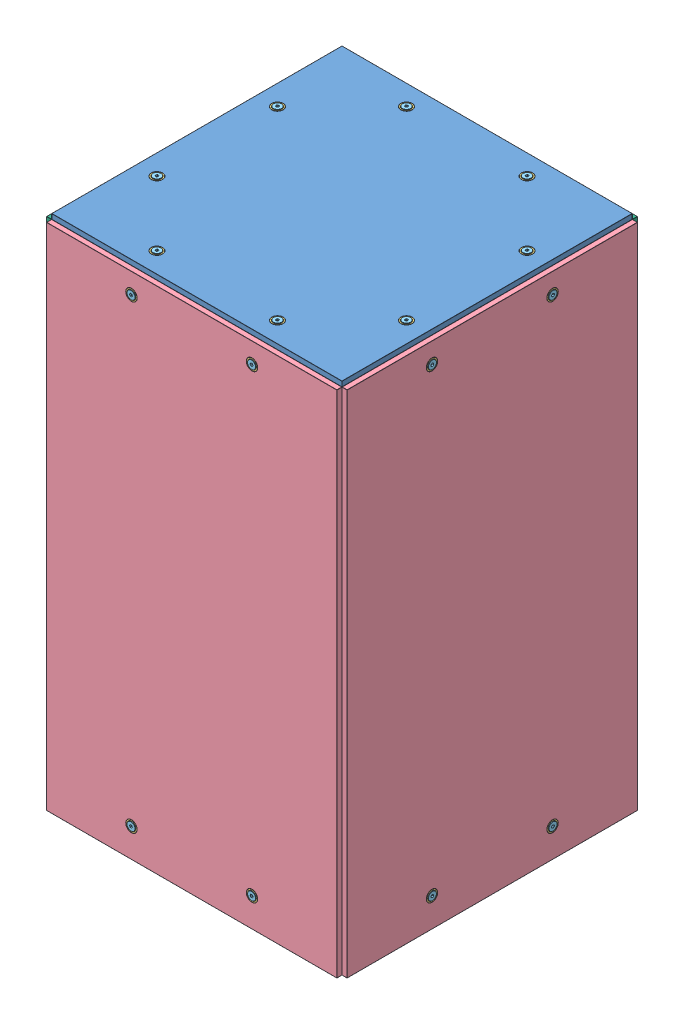
SolidWorks assembly SC.1.GD-PH, configuration Glass Dome 354 x 354 x 600. Lengths in mm.
Overall size (355.03 606.51 355.03).
85 component instances, 7 part files, 48 mates.
Components (placement in the parent):
- SC.1.G.PH.T-1: SC.1.G.PH.T [Topo 342 x 342] at (-2.0067 135.176 -92.8158)
- SC.1.L-1: SC.1.L [Default] at (-79.5067 117.926 60.9342) x (0 0 -1) z (1 0 0)
- SC.1.AC2-1: SC.1.AC2 [Default] at (-73.0067 136.176 54.1842) x (0 -1 0) z (0 0 1)
- SC.1.L-2: SC.1.L [Default] at (151.7433 117.926 -15.3158) x (-1 0 0) z (0 0 -1)
- SC.1.AC2-2: SC.1.AC2 [Default] at (144.9933 136.176 -21.8158) x (0 -1 0) z (0 0 1)
- SC.1.AC2-3: SC.1.AC2 [Default] at (68.9933 136.176 54.1842) x (0 -1 0) z (0 0 -1)
- SC.1.L-3: SC.1.L [Default] at (62.4933 117.926 60.9342) x (0 0 -1) z (1 0 0)
- SC.1.AC2-4: SC.1.AC2 [Default] at (144.9933 136.176 -163.8158) x (0 -1 0) z (0 0 1)
- SC.1.L-4: SC.1.L [Default] at (151.7433 117.926 -157.3158) x (-1 0 0) z (0 0 -1)
- SC.1.AC2-5: SC.1.AC2 [Default] at (-149.0067 136.176 -21.8158) x (0 -1 0) z (0 0 -1)
- SC.1.L-5: SC.1.L [Default] at (-155.7567 117.926 -28.3158)
- SC.1.AC2-6: SC.1.AC2 [Default] at (-149.0067 136.176 -163.8158) x (0 -1 0) z (0 0 -1)
- SC.1.L-6: SC.1.L [Default] at (-155.7567 117.926 -170.3158)
- SC.1.AC2-7: SC.1.AC2 [Default] at (68.9933 136.176 -239.8158) x (0 -1 0) z (0 0 -1)
- SC.1.L-7: SC.1.L [Default] at (75.4933 117.926 -246.5658) x (0 0 1) z (-1 0 0)
- SC.1.AC2-8: SC.1.AC2 [Default] at (-73.0067 136.176 -239.8158) x (0 -1 0) z (0 0 1)
- SC.1.L-8: SC.1.L [Default] at (-66.5067 117.926 -246.5658) x (0 0 1) z (-1 0 0)
- SC.1.G.PH.L-1: SC.1.G.PH.L [Lateral 342 x 600] at (-2.0067 -164.824 78.1842)
- SC.1.G.PH.L-5: SC.1.G.PH.L [Lateral 342 x 600] at (168.9933 -164.824 -92.8158) x (0 0 -1) z (1 0 0)
- SC.1.AC2-10: SC.1.AC2 [Default] at (-73.0067 111.176 79.1842) x (0 0 -1) z (0 -1 0)
- SC.1.AC2-11: SC.1.AC2 [Default] at (169.9933 111.176 -21.8158) x (-1 0 0) z (0 0 1)
- SC.1.P7991-12-1: SC.1.P7991-12 [ISO 10642 - M5 x 12 --- 12N] at (-73.0067 141.6902 54.1842) x (0 -1 0) z (0 0 1)
- SC.1.P7991-12-17: SC.1.P7991-12 [ISO 10642 - M5 x 12 --- 12N] at (-73.0067 111.176 84.6984) x (0 0 -1) z (0 -1 0)
- SC.1.P7991-12-21: SC.1.P7991-12 [ISO 10642 - M5 x 12 --- 12N] at (144.9933 141.6902 -21.8158) x (0 -1 0) z (0 0 1)
- SC.1.P7991-12-25: SC.1.P7991-12 [ISO 10642 - M5 x 12 --- 12N] at (175.5075 111.176 -21.8158) x (-1 0 0) z (0 0 1)
- SC.1.P7991-12-5: SC.1.P7991-12 [ISO 10642 - M5 x 12 --- 12N] at (68.9933 141.6902 54.1842) x (0 -1 0) z (0 0 -1)
- SC.1.P7991-12-18: SC.1.P7991-12 [ISO 10642 - M5 x 12 --- 12N] at (68.9933 111.176 84.6984) x (0 0 -1) z (0 1 0)
- SC.1.AC2-12: SC.1.AC2 [Default] at (68.9933 111.176 79.1842) x (0 0 -1) z (0 1 0)
- SC.1.P7991-12-22: SC.1.P7991-12 [ISO 10642 - M5 x 12 --- 12N] at (144.9933 141.6902 -163.8158) x (0 -1 0) z (0 0 1)
- SC.1.P7991-12-26: SC.1.P7991-12 [ISO 10642 - M5 x 12 --- 12N] at (175.5075 111.176 -163.8158) x (-1 0 0) z (0 0 1)
- SC.1.AC2-13: SC.1.AC2 [Default] at (169.9933 111.176 -163.8158) x (-1 0 0) z (0 0 1)
- SC.1.P7991-12-24: SC.1.P7991-12 [ISO 10642 - M5 x 12 --- 12N] at (-149.0067 141.6902 -21.8158) x (0 -1 0) z (0 0 -1)
- SC.1.AC2-14: SC.1.AC2 [Default] at (-174.0067 111.176 -21.8158) x (1 0 0) z (0 0 -1)
- SC.1.P7991-12-28: SC.1.P7991-12 [ISO 10642 - M5 x 12 --- 12N] at (-179.5209 111.176 -21.8158) x (1 0 0) z (0 0 -1)
- MirrorSC.1.G.PH.L-6: MirrorSC.1.G.PH.L [Lateral 342 x 600] at (-173.0067 -164.824 -92.8158) x (0 0 -1) z (1 0 0)
- SC.1.P7991-12-27: SC.1.P7991-12 [ISO 10642 - M5 x 12 --- 12N] at (-179.5209 111.176 -163.8158) x (1 0 0) z (0 0 -1)
- SC.1.AC2-15: SC.1.AC2 [Default] at (-174.0067 111.176 -163.8158) x (1 0 0) z (0 0 -1)
- SC.1.P7991-12-23: SC.1.P7991-12 [ISO 10642 - M5 x 12 --- 12N] at (-149.0067 141.6902 -163.8158) x (0 -1 0) z (0 0 -1)
- SC.1.P7991-12-20: SC.1.P7991-12 [ISO 10642 - M5 x 12 --- 12N] at (-73.0067 111.176 -270.33) x (0 0 1) z (0 1 0)
- SC.1.AC2-16: SC.1.AC2 [Default] at (-73.0067 111.176 -264.8158) x (0 0 1) z (0 1 0)
- SC.1.P7991-12-16: SC.1.P7991-12 [ISO 10642 - M5 x 12 --- 12N] at (-73.0067 141.6902 -239.8158) x (0 -1 0) z (0 0 1)
- SC.1.P7991-12-15: SC.1.P7991-12 [ISO 10642 - M5 x 12 --- 12N] at (68.9933 141.6902 -239.8158) x (0 -1 0) z (0 0 -1)
- SC.1.P7991-12-19: SC.1.P7991-12 [ISO 10642 - M5 x 12 --- 12N] at (68.9933 111.176 -270.33) x (0 0 1) z (0 -1 0)
- SC.1.AC2-17: SC.1.AC2 [Default] at (68.9933 111.176 -264.8158) x (0 0 1) z (0 -1 0)
- MirrorSC.1.G.PH.L-7: MirrorSC.1.G.PH.L [Lateral 342 x 600] at (-2.0067 -164.824 -263.8158)
- SC.1.P7991-12-29: SC.1.P7991-12 [ISO 10642 - M5 x 12 --- 12N] at (-73.0067 -430.824 84.6984) x (0 0 -1) z (-0.12915 -0.991625 0)
- SC.1.AC2-18: SC.1.AC2 [Default] at (-73.0067 -430.824 79.1842) x (0 0 -1) z (0 -1 0)
- SC.1.P7991-12-33: SC.1.P7991-12 [ISO 10642 - M5 x 12 --- 12N] at (175.5075 -430.824 -21.8158) x (-1 0 0) z (0 0 1)
- SC.1.AC2-19: SC.1.AC2 [Default] at (169.9933 -430.824 -21.8158) x (-1 0 0) z (0 0 1)
- SC.1.P7991-12-30: SC.1.P7991-12 [ISO 10642 - M5 x 12 --- 12N] at (68.9933 -430.824 84.6984) x (0 0 -1) z (-0.12915 0.991625 0)
- SC.1.AC2-20: SC.1.AC2 [Default] at (68.9933 -430.824 79.1842) x (0 0 -1) z (0 1 0)
- SC.1.P7991-12-34: SC.1.P7991-12 [ISO 10642 - M5 x 12 --- 12N] at (175.5075 -430.824 -163.8158) x (-1 0 0) z (0 0 1)
- SC.1.AC2-21: SC.1.AC2 [Default] at (169.9933 -430.824 -163.8158) x (-1 0 0) z (0 0 1)
- SC.1.P7991-12-36: SC.1.P7991-12 [ISO 10642 - M5 x 12 --- 12N] at (-179.5209 -430.824 -21.8158) x (1 0 0) z (0 0 -1)
- SC.1.AC2-22: SC.1.AC2 [Default] at (-174.0067 -430.824 -21.8158) x (1 0 0) z (0 0 -1)
- SC.1.P7991-12-35: SC.1.P7991-12 [ISO 10642 - M5 x 12 --- 12N] at (-179.5209 -430.824 -163.8158) x (1 0 0) z (0 0 -1)
- SC.1.AC2-23: SC.1.AC2 [Default] at (-174.0067 -430.824 -163.8158) x (1 0 0) z (0 0 -1)
- SC.1.AC2-24: SC.1.AC2 [Default] at (-73.0067 -430.824 -264.8158) x (0 0 1) z (0 1 0)
- SC.1.P7991-12-32: SC.1.P7991-12 [ISO 10642 - M5 x 12 --- 12N] at (-73.0067 -430.824 -270.33) x (0 0 1) z (0.12915 0.991625 0)
- SC.1.AC2-25: SC.1.AC2 [Default] at (68.9933 -430.824 -264.8158) x (0 0 1) z (0 -1 0)
- SC.1.P7991-12-31: SC.1.P7991-12 [ISO 10642 - M5 x 12 --- 12N] at (68.9933 -430.824 -270.33) x (0 0 1) z (0.12915 -0.991625 0)
- SC.1.A-1: SC.1.A [Default] at (-73.0067 131.176 54.1842) x (0 1 0) z (0 0 1) size (4 13 13)
- SC.1.A-2: SC.1.A [Default] at (-73.0067 111.176 78.1842) x (0 0 -1) z (-0.383049 0.923728 0) size (4 13 13)
- SC.1.A-4: SC.1.A [Default] at (-73.0067 -430.824 78.1842) x (0 0 -1) z (0 1 0) size (4 13 13)
- SC.1.A-5: SC.1.A [Default] at (144.9933 135.176 -21.8158) x (0 -1 0) z (-0.546944 0 0.837169) size (4 13 13)
- SC.1.A-6: SC.1.A [Default] at (168.9933 111.176 -21.8158) x (-1 0 0) z (0 0 1) size (4 13 13)
- SC.1.A-7: SC.1.A [Default] at (168.9933 -430.824 -21.8158) x (-1 0 0) z (0 0 1) size (4 13 13)
- SC.1.A-8: SC.1.A [Default] at (68.9933 131.176 54.1842) x (0 1 0) z (0 0 -1) size (4 13 13)
- SC.1.A-9: SC.1.A [Default] at (68.9933 111.176 78.1842) x (0 0 -1) z (-0.383049 -0.923728 0) size (4 13 13)
- SC.1.A-10: SC.1.A [Default] at (68.9933 -430.824 78.1842) x (0 0 -1) z (0 -1 0) size (4 13 13)
- SC.1.A-11: SC.1.A [Default] at (144.9933 135.176 -163.8158) x (0 -1 0) z (0.546944 0 0.837169) size (4 13 13)
- SC.1.A-12: SC.1.A [Default] at (168.9933 111.176 -163.8158) x (-1 0 0) z (0 0 1) size (4 13 13)
- SC.1.A-13: SC.1.A [Default] at (168.9933 -430.824 -163.8158) x (-1 0 0) z (0 0 1) size (4 13 13)
- SC.1.A-14: SC.1.A [Default] at (-173.0067 -430.824 -21.8158) x (1 0 0) z (0 0 -1) size (4 13 13)
- SC.1.A-15: SC.1.A [Default] at (-173.0067 -430.824 -163.8158) x (1 0 0) z (0 0 -1) size (4 13 13)
- SC.1.A-16: SC.1.A [Default] at (-173.0067 111.176 -21.8158) x (1 0 0) z (0 0 -1) size (4 13 13)
- SC.1.A-17: SC.1.A [Default] at (-173.0067 111.176 -163.8158) x (1 0 0) z (0 0 -1) size (4 13 13)
- SC.1.A-18: SC.1.A [Default] at (-149.0067 135.176 -163.8158) x (0 -1 0) z (0.546944 0 -0.837169) size (4 13 13)
- SC.1.A-19: SC.1.A [Default] at (-149.0067 135.176 -21.8158) x (0 -1 0) z (-0.546944 0 -0.837169) size (4 13 13)
- SC.1.A-20: SC.1.A [Default] at (-73.0067 -430.824 -263.8158) x (0 0 1) z (0 -1 0) size (4 13 13)
- SC.1.A-21: SC.1.A [Default] at (68.9933 -430.824 -263.8158) x (0 0 1) z (0 1 0) size (4 13 13)
- SC.1.A-22: SC.1.A [Default] at (-73.0067 111.176 -263.8158) x (0 0 1) z (0.383049 -0.923728 0) size (4 13 13)
- SC.1.A-23: SC.1.A [Default] at (-73.0067 131.176 -239.8158) x (0 1 0) z (0 0 1) size (4 13 13)
- SC.1.A-24: SC.1.A [Default] at (68.9933 111.176 -263.8158) x (0 0 1) z (0.383049 0.923728 0) size (4 13 13)
- SC.1.A-25: SC.1.A [Default] at (68.9933 131.176 -239.8158) x (0 1 0) z (0 0 -1) size (4 13 13)
Mates (geometry in assembly coordinates):
- Concentric3: concentric aligned: cylinder of SC.1.G.PH.T-1 through (-73.0067 135.176 54.1842) axis (0 1 0) radius 4; cylinder of SC.1.AC2-1 through (-73.0067 145.7556 54.1842) axis (0 1 0) radius 4
- Coincident2: coincident aligned: plane of SC.1.G.PH.T-1 through (-2.0067 141.176 -92.8158) normal (0 1 0); plane of SC.1.AC2-1 through (-66.5067 141.176 54.1842) normal (0 1 0)
- Concentric7: concentric aligned: cylinder of SC.1.L-1 through (-73.0067 131.176 54.1842) axis (0 1 0) radius 2.1; cylinder of SC.1.AC2-1 through (-73.0067 145.7556 54.1842) axis (0 1 0) radius 4
- Parallel1: parallel aligned: plane of SC.1.G.PH.T-1 through (-173.0067 141.176 78.1842) normal (0 0 1); plane of SC.1.L-1 through (-66.5067 131.176 74.1842) normal (0 0 1)
- Concentric10: concentric aligned: cylinder of SC.1.L-2 through (144.9933 131.176 -21.8158) axis (0 1 0) radius 2.1; cylinder of SC.1.AC2-2 through (144.9933 145.7556 -21.8158) axis (0 1 0) radius 4
- Concentric11: concentric aligned: cylinder of SC.1.G.PH.T-1 through (144.9933 135.176 -21.8158) axis (0 1 0) radius 4; cylinder of SC.1.AC2-2 through (144.9933 145.7556 -21.8158) axis (0 1 0) radius 4
- Coincident9: coincident aligned: plane of SC.1.G.PH.T-1 through (-2.0067 141.176 -92.8158) normal (0 1 0); plane of SC.1.AC2-2 through (151.4933 141.176 -21.8158) normal (0 1 0)
- Parallel2: parallel aligned: plane of SC.1.G.PH.T-1 through (168.9933 141.176 -263.8158) normal (1 0 0); plane of SC.1.L-2 through (164.9933 131.176 -28.3158) normal (1 0 0)
- Concentric16: concentric aligned: cylinder of SC.1.L-1 through (-73.0067 111.176 74.1842) axis (0 0 1) radius 2.1; cylinder of SC.1.G.PH.L-1 through (-73.0067 111.176 78.1842) axis (0 0 1) radius 4
- Concentric17: concentric aligned: cylinder of SC.1.L-3 through (68.9933 111.176 74.1842) axis (0 0 1) radius 2.1; cylinder of SC.1.G.PH.L-1 through (68.9933 111.176 78.1842) axis (0 0 1) radius 4
- Concentric20: concentric aligned: cylinder of SC.1.L-2 through (164.9933 111.176 -21.8158) axis (1 0 0) radius 2.1; cylinder of SC.1.G.PH.L-5 through (168.9933 111.176 -21.8158) axis (1 0 0) radius 4
- Concentric21: concentric aligned: cylinder of SC.1.L-4 through (164.9933 111.176 -163.8158) axis (1 0 0) radius 2.1; cylinder of SC.1.G.PH.L-5 through (168.9933 111.176 -163.8158) axis (1 0 0) radius 4
- Concentric22: concentric aligned: cylinder of SC.1.G.PH.L-1 through (-73.0067 111.176 78.1842) axis (0 0 1) radius 4; cylinder of SC.1.AC2-10 through (-73.0067 111.176 88.7638) axis (0 0 1) radius 4
- Coincident21: coincident aligned: plane of SC.1.G.PH.L-1 through (-2.0067 -164.824 84.1842) normal (0 0 1); plane of SC.1.AC2-10 through (-66.5067 111.176 84.1842) normal (0 0 1)
- Concentric23: concentric aligned: cylinder of SC.1.G.PH.L-5 through (168.9933 111.176 -21.8158) axis (1 0 0) radius 4; cylinder of SC.1.AC2-11 through (179.5729 111.176 -21.8158) axis (1 0 0) radius 4
- Coincident22: coincident aligned: plane of SC.1.G.PH.L-5 through (174.9933 -164.824 -92.8158) normal (1 0 0); plane of SC.1.AC2-11 through (174.9933 104.676 -21.8158) normal (1 0 0)
- Concentric24: concentric aligned: cylinder of SC.1.AC2-1 through (-73.0067 145.7556 54.1842) axis (0 1 0) radius 4; cylinder of SC.1.P7991-12-1 through (-73.0067 141.6902 54.1842) axis (0 1 0) radius 2.5
- Coincident23: coincident aligned: cone of SC.1.AC2-1 through (-73.0067 141.176 54.1842) axis (0 -1 0); cone of SC.1.P7991-12-1 through (-73.0067 140.8052 54.1842) axis (0 -1 0)
- Concentric26: concentric aligned: cylinder of SC.1.AC2-10 through (-73.0067 111.176 88.7638) axis (0 0 1) radius 4; cylinder of SC.1.P7991-12-17 through (-73.0067 111.176 84.6984) axis (0 0 1) radius 2.5
- Coincident24: coincident: cone of SC.1.AC2-10 through (-73.0067 111.176 84.1842) axis (0 0 -1); cone of SC.1.P7991-12-17 through (-73.0067 111.176 83.8134) axis (0 0 -1)
- Concentric27: concentric aligned: cylinder of SC.1.AC2-2 through (144.9933 145.7556 -21.8158) axis (0 1 0) radius 4; cylinder of SC.1.P7991-12-21 through (144.9933 141.6902 -21.8158) axis (0 1 0) radius 2.5
- Coincident25: coincident aligned: cone of SC.1.AC2-2 through (144.9933 141.176 -21.8158) axis (0 -1 0); cone of SC.1.P7991-12-21 through (144.9933 140.8052 -21.8158) axis (0 -1 0)
- Concentric28: concentric aligned: cylinder of SC.1.AC2-11 through (179.5729 111.176 -21.8158) axis (1 0 0) radius 4; cylinder of SC.1.P7991-12-25 through (175.5075 111.176 -21.8158) axis (1 0 0) radius 2.5
- Coincident26: coincident aligned: cone of SC.1.AC2-11 through (174.9933 111.176 -21.8158) axis (-1 0 0); cone of SC.1.P7991-12-25 through (174.6225 111.176 -21.8158) axis (-1 0 0)
- Concentric31: concentric aligned: cylinder of SC.1.P7991-12-29 through (-73.0067 -430.824 84.6984) axis (0 0 1) radius 2.5; cylinder of SC.1.AC2-18 through (-73.0067 -430.824 88.7638) axis (0 0 1) radius 4
- Coincident28: coincident aligned: cone of SC.1.P7991-12-29 through (-73.0067 -430.824 83.8134) axis (0 0 -1); cone of SC.1.AC2-18 through (-73.0067 -430.824 84.1842) axis (0 0 -1)
- Concentric32: concentric aligned: cylinder of SC.1.G.PH.L-1 through (-73.0067 -430.824 78.1842) axis (0 0 1) radius 4; cylinder of SC.1.AC2-18 through (-73.0067 -430.824 88.7638) axis (0 0 1) radius 4
- Coincident29: coincident aligned: plane of SC.1.G.PH.L-1 through (-2.0067 -164.824 84.1842) normal (0 0 1); plane of SC.1.AC2-18 through (-66.5067 -430.824 84.1842) normal (0 0 1)
- Concentric35: concentric aligned: cylinder of SC.1.P7991-12-33 through (175.5075 -430.824 -21.8158) axis (1 0 0) radius 2.5; cylinder of SC.1.AC2-19 through (179.5729 -430.824 -21.8158) axis (1 0 0) radius 4
- Coincident32: coincident aligned: cone of SC.1.P7991-12-33 through (174.6225 -430.824 -21.8158) axis (-1 0 0); cone of SC.1.AC2-19 through (174.9933 -430.824 -21.8158) axis (-1 0 0)
- Concentric36: concentric aligned: cylinder of SC.1.G.PH.L-5 through (168.9933 -430.824 -21.8158) axis (1 0 0) radius 4; cylinder of SC.1.AC2-19 through (179.5729 -430.824 -21.8158) axis (1 0 0) radius 4
- Coincident33: coincident aligned: plane of SC.1.G.PH.L-5 through (174.9933 -164.824 -92.8158) normal (1 0 0); plane of SC.1.AC2-19 through (174.9933 -437.324 -21.8158) normal (1 0 0)
- Coincident34: coincident anti-aligned: plane of SC.1.L-1 through (-66.5067 131.176 47.6842) normal (0 1 0); plane of SC.1.AC2-1 through (-69.0067 131.176 54.1842) normal (0 -1 0)
- Coincident35: coincident anti-aligned: plane of SC.1.L-1 through (-66.5067 131.176 74.1842) normal (0 0 1); plane of SC.1.AC2-10 through (-69.0067 111.176 74.1842) normal (0 0 -1)
- Coincident36: coincident anti-aligned: plane of SC.1.L-2 through (138.4933 131.176 -28.3158) normal (0 1 0); plane of SC.1.AC2-2 through (148.9933 131.176 -21.8158) normal (0 -1 0)
- Coincident37: coincident anti-aligned: plane of SC.1.L-2 through (164.9933 131.176 -28.3158) normal (1 0 0); plane of SC.1.AC2-11 through (164.9933 107.176 -21.8158) normal (-1 0 0)
- Coincident39: coincident anti-aligned: plane of SC.1.L-1 through (-66.5067 131.176 47.6842) normal (0 1 0); plane of SC.1.A-1 through (-73.0067 131.176 54.1842) normal (0 -1 0)
- Concentric37: concentric anti-aligned: cylinder of SC.1.AC2-1 through (-73.0067 145.7556 54.1842) axis (0 1 0) radius 4; cylinder of SC.1.A-1 through (-73.0067 135.176 54.1842) axis (0 -1 0) radius 4
- Concentric38: concentric aligned: cylinder of SC.1.AC2-10 through (-73.0067 111.176 88.7638) axis (0 0 1) radius 4; cylinder of SC.1.A-2 through (-73.0067 111.176 74.1842) axis (0 0 1) radius 4
- Coincident40: coincident anti-aligned: plane of SC.1.G.PH.L-1 through (-2.0067 -164.824 78.1842) normal (0 0 -1); plane of SC.1.A-2 through (-73.0067 111.176 78.1842) normal (0 0 1)
- Coincident42: coincident anti-aligned: plane of SC.1.G.PH.L-1 through (-2.0067 -164.824 78.1842) normal (0 0 -1); plane of SC.1.A-4 through (-73.0067 -430.824 78.1842) normal (0 0 1)
- Concentric40: concentric aligned: cylinder of SC.1.AC2-18 through (-73.0067 -430.824 88.7638) axis (0 0 1) radius 4; cylinder of SC.1.A-4 through (-73.0067 -430.824 74.1842) axis (0 0 1) radius 4
- Coincident43: coincident anti-aligned: plane of SC.1.G.PH.T-1 through (-2.0067 135.176 -92.8158) normal (0 -1 0); plane of SC.1.A-5 through (144.9933 135.176 -21.8158) normal (0 1 0)
- Concentric41: concentric aligned: cylinder of SC.1.AC2-2 through (144.9933 145.7556 -21.8158) axis (0 1 0) radius 4; cylinder of SC.1.A-5 through (144.9933 131.176 -21.8158) axis (0 1 0) radius 4
- Coincident44: coincident anti-aligned: plane of SC.1.G.PH.L-5 through (168.9933 -164.824 -92.8158) normal (-1 0 0); plane of SC.1.A-6 through (168.9933 111.176 -21.8158) normal (1 0 0)
- Concentric42: concentric aligned: cylinder of SC.1.AC2-11 through (179.5729 111.176 -21.8158) axis (1 0 0) radius 4; cylinder of SC.1.A-6 through (164.9933 111.176 -21.8158) axis (1 0 0) radius 4
- Coincident45: coincident anti-aligned: plane of SC.1.G.PH.L-5 through (168.9933 -164.824 -92.8158) normal (-1 0 0); plane of SC.1.A-7 through (168.9933 -430.824 -21.8158) normal (1 0 0)
- Concentric43: concentric aligned: cylinder of SC.1.AC2-19 through (179.5729 -430.824 -21.8158) axis (1 0 0) radius 4; cylinder of SC.1.A-7 through (164.9933 -430.824 -21.8158) axis (1 0 0) radius 4
